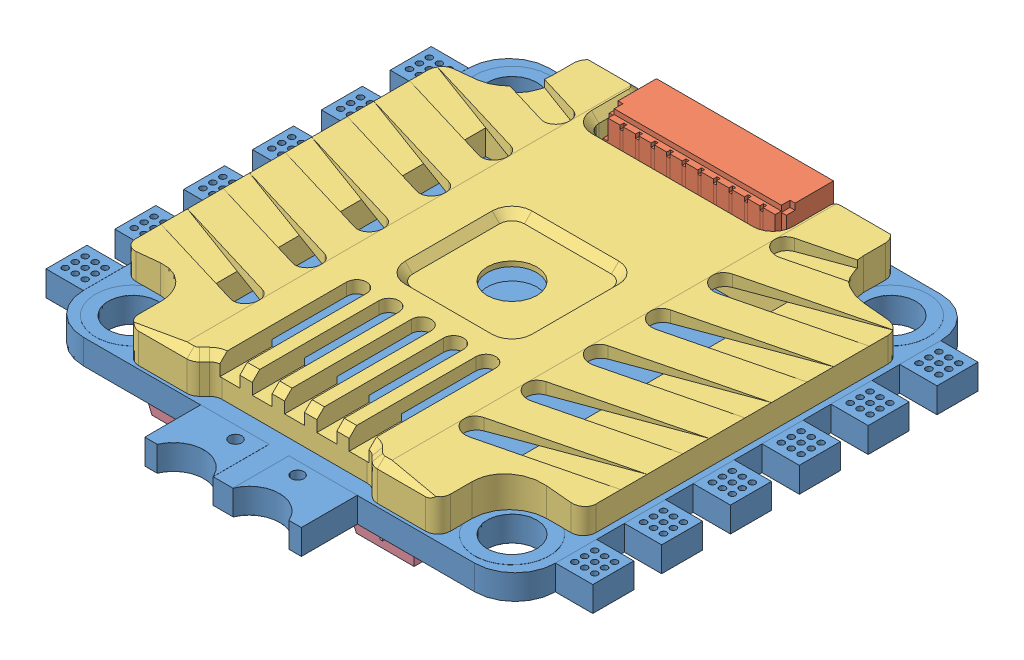
SolidWorks assembly F45A, configuration Default. Lengths in mm.
Overall size (119.92 7.18 42).
38 component instances, 5 part files, 39 mates.
Components (placement in the parent):
- F45A PCB-1: F45A PCB [Default] at origin size (44 3.01 42)
- DF13-10P-1: DF13-10P [Default] at (3.125 2.88 -16.6) x (-1 0 0) z (0 0 -1) size (14.25 3.58 5.1)
- Heat Sink-1: Heat Sink [Default] at (0 2.5 0) size (116.42 3 37)
- TPH1R403NL-1: TPH1R403NL [Default] at (8.2237 -1 16.1) x (0 0 -1) z (-1 0 0) size (5.3 1 6)
- TPH1R403NL-2: TPH1R403NL [Default] at (8.5237 -1 9.95) x (-1 0 0) z (0 0 1) size (5.3 1 6)
- TPH1R403NL-3: TPH1R403NL [Default] at (14.6737 -1 9.0737) x (0 0 1) z (1 0 0) size (5.3 1 6)
- TPH1R403NL-4: TPH1R403NL [Default] at (14.6737 -1 2.8237) x (0 0 1) z (1 0 0) size (5.3 1 6)
- TPH1R403NL-9: TPH1R403NL [Default] at (-8.2237 -1 16.1) x (0 0 1) z (1 0 0) size (5.3 1 6)
- TPH1R403NL-10: TPH1R403NL [Default] at (-14.6737 -1 2.8237) x (0 0 -1) z (-1 0 0) size (5.3 1 6)
- TPH1R403NL-11: TPH1R403NL [Default] at (-14.6737 -1 9.0737) x (0 0 -1) z (-1 0 0) size (5.3 1 6)
- TPH1R403NL-13: TPH1R403NL [Default] at (8.2237 -1 -16.1) x (0 0 -1) z (-1 0 0) size (5.3 1 6)
- TPH1R403NL-14: TPH1R403NL [Default] at (14.6737 -1 -2.8237) x (0 0 1) z (1 0 0) size (5.3 1 6)
- TPH1R403NL-15: TPH1R403NL [Default] at (14.6737 -1 -9.0737) x (0 0 1) z (1 0 0) size (5.3 1 6)
- TPH1R403NL-17: TPH1R403NL [Default] at (-8.2237 -1 -16.1) x (0 0 1) z (1 0 0) size (5.3 1 6)
- TPH1R403NL-18: TPH1R403NL [Default] at (-14.6737 -1 -2.8237) x (0 0 -1) z (-1 0 0) size (5.3 1 6)
- TPH1R403NL-19: TPH1R403NL [Default] at (-14.6737 -1 -9.0737) x (0 0 -1) z (-1 0 0) size (5.3 1 6)
- TPH1R403NL-21: TPH1R403NL [Default] at (-8.5237 -1 9.95) x (-1 0 0) z (0 0 1) size (5.3 1 6)
- TPH1R403NL-23: TPH1R403NL [Default] at (-8.5237 -1 -9.95) x (1 0 0) z (0 0 -1) size (5.3 1 6)
- TPH1R403NL-24: TPH1R403NL [Default] at (8.5237 -1 -9.95) x (1 0 0) z (0 0 -1) size (5.3 1 6)
- Capacitor-1: Capacitor [Default] at (9.5737 -1 -1.95) x (-1 0 0) z (0 0 1) size (3.2 1.5 1.6)
- Capacitor-5: Capacitor [Default] at (9.5737 -1 -0.15) x (-1 0 0) z (0 0 1) size (3.2 1.5 1.6)
- Capacitor-6: Capacitor [Default] at (9.5737 -1 1.65) x (-1 0 0) z (0 0 1) size (3.2 1.5 1.6)
- Capacitor-7: Capacitor [Default] at (9.5737 -1 3.45) x (-1 0 0) z (0 0 1) size (3.2 1.5 1.6)
- Capacitor-8: Capacitor [Default] at (-9.5737 -1 -1.95) x (-1 0 0) z (0 0 1) size (3.2 1.5 1.6)
- Capacitor-9: Capacitor [Default] at (-9.5737 -1 -0.15) x (-1 0 0) z (0 0 1) size (3.2 1.5 1.6)
- Capacitor-10: Capacitor [Default] at (-9.5737 -1 1.65) x (-1 0 0) z (0 0 1) size (3.2 1.5 1.6)
- Capacitor-11: Capacitor [Default] at (-9.5737 -1 3.45) x (-1 0 0) z (0 0 1) size (3.2 1.5 1.6)
- Capacitor-12: Capacitor [Default] at (5.3737 -1.8 -8.35) x (0 0 1) z (0 -1 0) size (3.2 1.5 1.6)
- Capacitor-13: Capacitor [Default] at (3.5737 -1.8 -8.35) x (0 0 1) z (0 -1 0) size (3.2 1.5 1.6)
- Capacitor-14: Capacitor [Default] at (1.7737 -1.8 -8.35) x (0 0 1) z (0 -1 0) size (3.2 1.5 1.6)
- Capacitor-15: Capacitor [Default] at (-0.0263 -1.8 -8.35) x (0 0 1) z (0 -1 0) size (3.2 1.5 1.6)
- Capacitor-16: Capacitor [Default] at (-1.8263 -1.8 -8.35) x (0 0 1) z (0 -1 0) size (3.2 1.5 1.6)
- Capacitor-17: Capacitor [Default] at (5.3737 -1.8 10.75) x (0 0 1) z (0 -1 0) size (3.2 1.5 1.6)
- Capacitor-18: Capacitor [Default] at (3.5737 -1.8 10.75) x (0 0 1) z (0 -1 0) size (3.2 1.5 1.6)
- Capacitor-19: Capacitor [Default] at (1.7737 -1.8 10.75) x (0 0 1) z (0 -1 0) size (3.2 1.5 1.6)
- Capacitor-20: Capacitor [Default] at (-0.0263 -1.8 10.75) x (0 0 1) z (0 -1 0) size (3.2 1.5 1.6)
- Capacitor-21: Capacitor [Default] at (-1.8263 -1.8 10.75) x (0 0 1) z (0 -1 0) size (3.2 1.5 1.6)
- Capacitor-22: Capacitor [Default] at (-4.4263 -2.5 10.75) x (0 0 1) z (-1 0 0) size (3.2 1.5 1.6)
Mates (geometry in assembly coordinates):
- Coincident1: coincident anti-aligned: plane of F45A PCB-1 through (0 1 0) normal (0 1 0); plane of DF13-10P-1 through (5.5 1 -14.75) normal (0 -1 0)
- Coincident2: coincident aligned: plane of F45A PCB-1 through (19 1 -18.75) normal (0 0 -1); plane of DF13-10P-1 through (-3.125 2.88 -18.75) normal (0 0 -1)
- Width1: width anti-aligned: plane of DF13-10P-1 through (-7.125 1.18 -18.75) normal (-1 0 0); plane of DF13-10P-1 through (7.125 1.18 -18.75) normal (1 0 0); plane of F45A PCB-1 through (19 1 18.75) normal (1 0 0); plane of F45A PCB-1 through (-19 1 18.75) normal (-1 0 0)
- Coincident3: coincident anti-aligned: plane of F45A PCB-1 through (0 1 0) normal (0 1 0); plane of Heat Sink-1 through (-15.5428 1 -15.75) normal (0 -1 0)
- Coincident4: coincident aligned: plane of F45A PCB-1 through (0 0 0) normal (1 0 0); plane of Heat Sink-1 through (0 2.5 0) normal (1 0 0)
- Coincident5: coincident aligned: plane of F45A PCB-1 through (0 0 0) normal (0 0 1); plane of Heat Sink-1 through (0 2.5 0) normal (0 0 1)
- Coincident6: coincident anti-aligned: plane of F45A PCB-1 through (0 -1 0) normal (0 -1 0); plane of TPH1R403NL-1 through (8.2237 -1 16.1) normal (0 1 0)
- Coincident7: coincident aligned: plane of F45A PCB-1 through (19 1 18.75) normal (0 0 1); plane of TPH1R403NL-1 through (8.1237 -1 18.75) normal (0 0 1)
- Distance2: distance = 16.1 mm: line of TPH1R403NL-1 through (5.9 -2 18.4237) axis (0 0 -1); plane of F45A PCB-1 through (22 -5.4598 12.2) normal (1 0 0)
- Coincident8: coincident anti-aligned: plane of F45A PCB-1 through (0 -1 0) normal (0 -1 0); plane of TPH1R403NL-2 through (8.5237 -1 9.95) normal (0 1 0)
- Distance3: distance = 0.5 mm anti-aligned: plane of TPH1R403NL-2 through (6.4187 -1 12.95) normal (0 0 1); plane of TPH1R403NL-1 through (8.3237 -1 13.45) normal (0 0 -1)
- Distance4: distance = 15.8 mm: line of TPH1R403NL-2 through (6.2 -2 12.2737) axis (0 0 -1); plane of F45A PCB-1 through (22 -5.4598 6.66) normal (1 0 0)
- Coincident9: coincident anti-aligned: plane of F45A PCB-1 through (0 -1 0) normal (0 -1 0); plane of TPH1R403NL-3 through (14.6737 -1 9.0737) normal (0 1 0)
- Distance5: distance = 0.5 mm anti-aligned: plane of TPH1R403NL-3 through (11.6737 -1 9.5087) normal (-1 0 0); plane of TPH1R403NL-2 through (11.1737 -1 10.05) normal (1 0 0)
- Distance6: distance = 12 mm: line of TPH1R403NL-3 through (12.35 -2 6.75) axis (1 0 0); plane of F45A PCB-1 through (19 1 18.75) normal (0 0 1)
- Coincident10: coincident anti-aligned: plane of F45A PCB-1 through (0 -1 0) normal (0 -1 0); plane of TPH1R403NL-4 through (14.6737 -1 2.8237) normal (0 1 0)
- Coincident11: coincident aligned: plane of TPH1R403NL-3 through (17.6737 -1 7.3687) normal (1 0 0); plane of TPH1R403NL-4 through (17.6737 -1 3.6587) normal (1 0 0)
- Distance7: distance = 1.25 mm: line of TPH1R403NL-4 through (14.5737 -1 5.3237) axis (-1 0 0); line of TPH1R403NL-3 through (12.1737 -1 6.5737) axis (1 0 0)
- Coincident12: coincident anti-aligned: plane of F45A PCB-1 through (0 -1 0) normal (0 -1 0); plane of TPH1R403NL-21 through (-8.5237 -1 9.95) normal (0 1 0)
- Coincident13: coincident aligned: plane of TPH1R403NL-2 through (7.6887 -1 12.95) normal (0 0 1); plane of TPH1R403NL-21 through (-8.0887 -1 12.95) normal (0 0 1)
- Distance8: distance = 0.65 mm aligned: plane of TPH1R403NL-9 through (-5.2237 -1 14.395) normal (1 0 0); plane of TPH1R403NL-21 through (-5.8737 -1 10.05) normal (1 0 0)
- Coincident14: coincident anti-aligned: plane of F45A PCB-1 through (0 -1 0) normal (0 -1 0); plane of TPH1R403NL-23 through (-8.5237 -1 -9.95) normal (0 1 0)
- Coincident15: coincident aligned: plane of TPH1R403NL-21 through (-5.8737 -1 10.05) normal (1 0 0); plane of TPH1R403NL-23 through (-5.8737 -1 -9.85) normal (1 0 0)
- Distance9: distance = 0.5 mm anti-aligned: plane of TPH1R403NL-23 through (-8.9587 -1 -12.95) normal (0 0 -1); plane of TPH1R403NL-17 through (-8.3237 -1 -13.45) normal (0 0 1)
- Coincident16: coincident anti-aligned: plane of F45A PCB-1 through (0 -1 0) normal (0 -1 0); plane of TPH1R403NL-24 through (8.5237 -1 -9.95) normal (0 1 0)
- Coincident17: coincident aligned: plane of TPH1R403NL-23 through (-9.3587 -1 -6.95) normal (0 0 1); plane of TPH1R403NL-24 through (7.6887 -1 -6.95) normal (0 0 1)
- Coincident18: coincident aligned: plane of TPH1R403NL-2 through (11.1737 -1 10.05) normal (1 0 0); plane of TPH1R403NL-24 through (11.1737 -1 -9.85) normal (1 0 0)
- Coincident19: coincident anti-aligned: plane of F45A PCB-1 through (0 -1 0) normal (0 -1 0); plane of Condenser-4
- Coincident20: coincident anti-aligned: plane of F45A PCB-1 through (0 -1 0) normal (0 -1 0); plane of Condenser-3
- Coincident21: coincident anti-aligned: plane of F45A PCB-1 through (0 -1 0) normal (0 -1 0); plane of Condenser-2
- Coincident22: coincident anti-aligned: plane of F45A PCB-1 through (0 -1 0) normal (0 -1 0); plane of Condenser-1 through (9.5737 -1 -1.95) normal (0 1 0)
- Distance10: distance = 17.6 mm anti-aligned: plane of Condenser-1 through (8.4737 -2.5 -1.15) normal (0 0 1); plane of F45A PCB-1 through (19 1 -18.75) normal (0 0 -1)
- Distance11: distance = 0.5 mm anti-aligned: plane of Condenser-1 through (11.1737 -2.35 -1.3) normal (1 0 0); plane of TPH1R403NL-14 through (11.6737 -1 -2.3887) normal (-1 0 0)
- Coincident24: coincident anti-aligned: plane of F45A PCB-1 through (0 -1 0) normal (0 -1 0); plane of Condenser-12 through (3.8737 -1 -7.25) normal (0 1 0)
- Distance13: distance = 0.1 mm aligned: plane of Condenser-12 through (4.0237 -2.45 -9.95) normal (0 0 -1); plane of TPH1R403NL-24 through (6.2069 -1 -10.05) normal (0 0 -1)
- Distance14: distance = 0.5 mm anti-aligned: plane of TPH1R403NL-2 through (5.8737 -1 9.85) normal (-1 0 0); plane of Condenser-12 through (5.3737 -1.8 -8.35) normal (1 0 0)
- Coincident25: coincident anti-aligned: plane of F45A PCB-1 through (0 -1 0) normal (0 -1 0); plane of Condenser-22 through (-4.4263 -1 10.75) normal (0 1 0)
- Coincident26: coincident aligned: plane of Condenser-21 through (-3.1763 -2.45 9.15) normal (0 0 -1); plane of Condenser-22 through (-5.0763 -1.15 9.15) normal (0 0 -1)
- Distance16: distance = 0.3 mm anti-aligned: plane of Condenser-21 through (-3.3263 -1.8 10.75) normal (-1 0 0); plane of Condenser-22 through (-3.6263 -1 11.85) normal (1 0 0)
